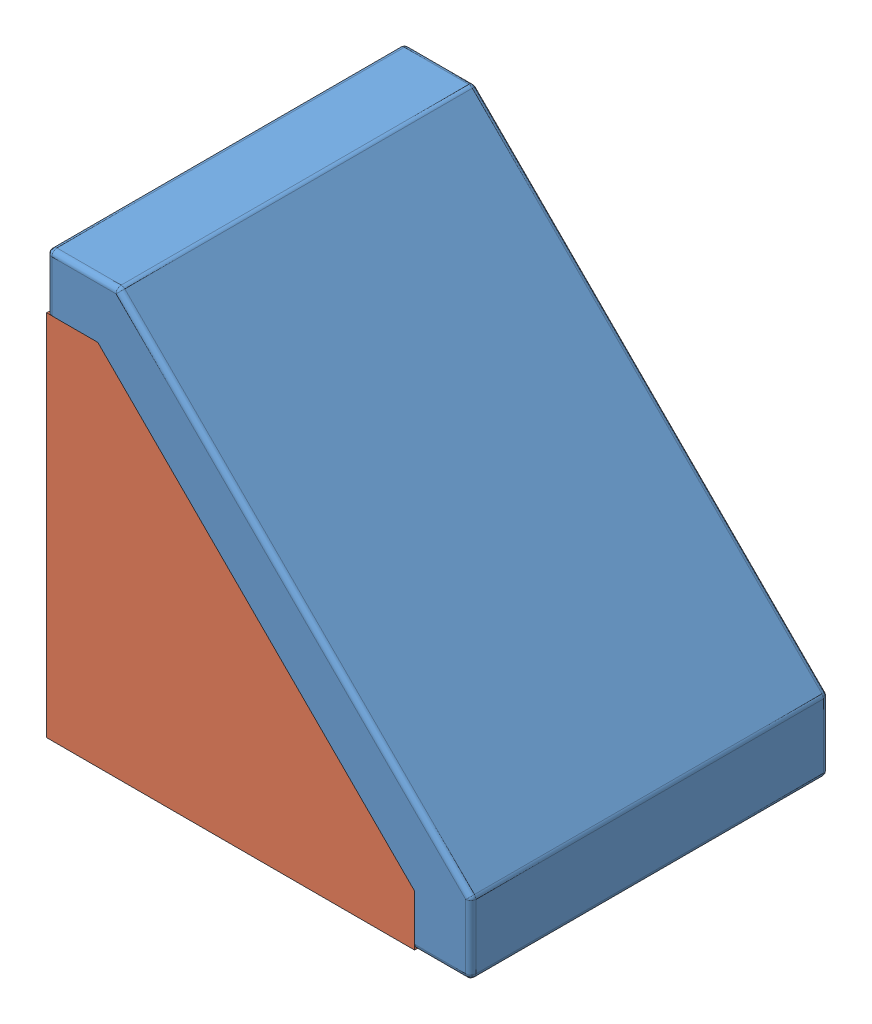
SolidWorks assembly СБУголок40Заглушка, configuration По умолчанию. Lengths in mm.
Overall size (45.62 45.61 35).
2 component instances, 2 part files, 3 mates.
Components (placement in the parent):
- Заглушка для уголка 40 серии 10 паз усиленная-1: Заглушка для уголка 40 серии 10 паз усиленная [По умолчанию] at (-80.8377 -28.2613 33.8191) size (41.5 41.5 35)
- Уголок 40 серия 10 паз (38х36х36) усиленный-1: Уголок 40 серия 10 паз (38х36х36) усиленный [По умолчанию] at (-80.8377 -28.2567 33.8191) size (40.12 40.12 35)
Mates (geometry in assembly coordinates):
- Совпадение5: coincident anti-aligned: plane of Заглушка для уголка 40 серии 10 паз усиленная-1 through (-44.8377 -23.2567 16.3191) normal (-0.707107 -0.707107 0); plane of Уголок 40 серия 10 паз (38х36х36) усиленный-1 through (-75.8377 7.7433 16.3191) normal (0.707107 0.707107 0)
- Совпадение6: coincident aligned: plane of Заглушка для уголка 40 серии 10 паз усиленная-1 through (-80.8377 -28.2613 51.3191) normal (0 0 1); plane of Уголок 40 серия 10 паз (38х36х36) усиленный-1 through (-80.8377 -28.2567 51.3191) normal (0 0 1)
- Совпадение7: coincident aligned: plane of Заглушка для уголка 40 серии 10 паз усиленная-1 through (-80.8377 7.7387 16.3191) normal (-1 0 0); plane of Уголок 40 серия 10 паз (38х36х36) усиленный-1 through (-80.8377 -28.2567 16.3191) normal (-1 0 0)
